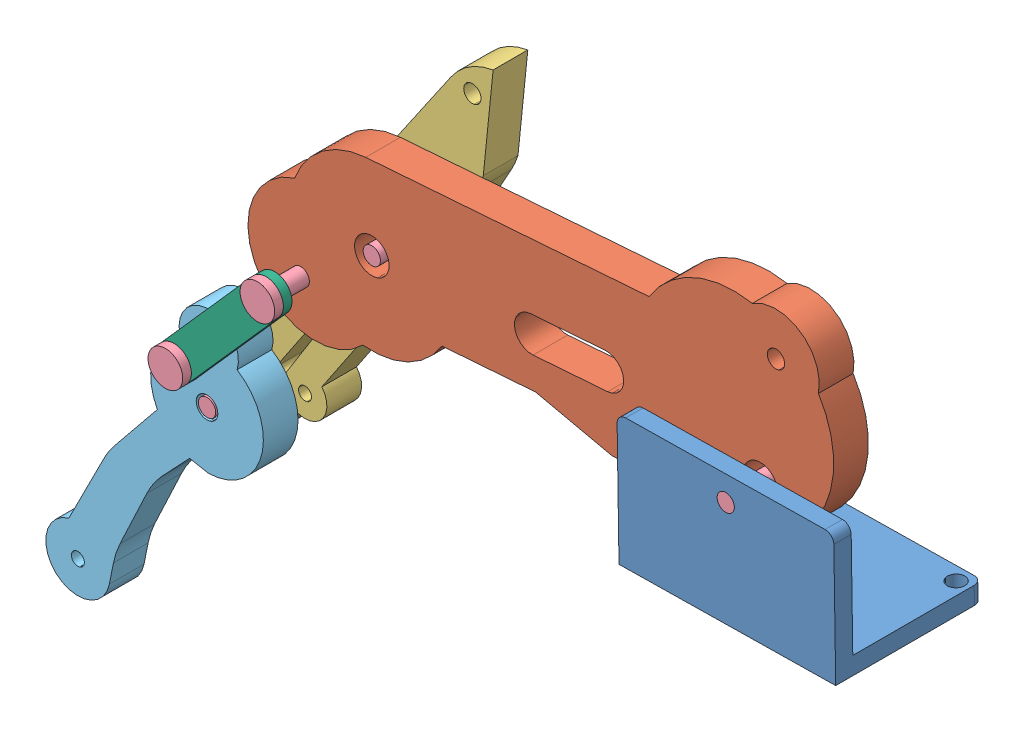
SolidWorks assembly Assem1, configuration Default. Lengths in mm.
Overall size (98.82 77.15 18.06).
10 component instances, 6 part files, 20 mates.
Components (placement in the parent):
- Base-union-1: Base-union [Default] at (40.7368 34.9498 5.6422) x (0.999881 0.015442 0) z (0.015442 -0.999881 0) size (25.11 17.06 15.06)
- Dedo-inferior-1: Dedo-inferior [Default] at (-16.736 45.1395 -0.3578) x (0.997247 0.074154 0) z (0 0 1) size (68.17 25.78 4)
- Dedo-medio-1: Dedo-medio [Default] at (-38.1998 17.0042 -4.3578) x (0.558156 0.829736 0) z (0 0 1) size (59.03 11.38 4)
- Tornillo-0.10-1: Tornillo-0.10 [Default] at (-24.9374 38.9522 -0.3578) x (0.645348 0.763888 0) z (0 0 1) size (4 4 9)
- Tornillo-0.10-2: Tornillo-0.10 [Default] at (-16.736 45.1395 3.6422) x (-0.566388 -0.824139 0) z (0 0 -1) size (4 4 9)
- Tornillo-0.10-3: Tornillo-0.10 [Default] at (28.0815 44.9037 7.6422) x (-0.923728 -0.383049 0) z (0 0 -1) size (4 4 9)
- Tornillo-0.10-4: Tornillo-0.10 [Default] at (-35.5482 26.9767 -0.3578) x (0.999969 -0.007893 0) z (0 0 1) size (4 4 9)
- Tornillo-0.10-5: Tornillo-0.10 [Default] at (-35.7445 20.4797 3.6422) x (0.262 -0.965068 0) z (0 0 -1) size (4 4 9)
- Dedo-punta-1: Dedo-punta [Default] at (-63.5967 -8.6033 -0.3578) x (0.538822 0.84242 0) z (0 0 1) size (39.74 13.26 4)
- Union-2cm-1: Union-2cm [Default] at (-35.5482 26.9767 6.6422) x (0.663175 0.748465 0) z (0 0 1) size (20 4 1)
Mates (geometry in assembly coordinates):
- Concentric6: concentric aligned: circle of Dedo-inferior-1; circle of Tornillo-0.10-1
- Concentric7: concentric aligned: cylinder of Dedo-inferior-1 through (-24.9374 38.9522 3.6422) axis (0 0 -1) radius 1; cylinder of Tornillo-0.10-1 through (-24.9374 38.9522 7.6422) axis (0 0 -1) radius 1
- Coincident10: coincident anti-aligned: plane of Dedo-inferior-1 through (-16.736 45.1395 -0.3578) normal (0 0 -1); circle of Tornillo-0.10-1
- Concentric8: concentric anti-aligned: cylinder of Dedo-inferior-1 through (28.0815 44.9037 3.6422) axis (0 0 -1) radius 2; cylinder of Tornillo-0.10-3 through (28.0815 44.9037 -0.3578) axis (0 0 1) radius 1
- Coincident11: coincident anti-aligned: plane of Dedo-inferior-1 through (-16.736 45.1395 -0.3578) normal (0 0 -1); plane of Tornillo-0.10-3 through (28.0815 44.9037 -0.3578) normal (0 0 1)
- Concentric9: concentric aligned: cylinder of Base-union-1 through (28.0815 44.9037 -24.3578) axis (0 0 1) radius 1; cylinder of Tornillo-0.10-3 through (28.0815 44.9037 -0.3578) axis (0 0 1) radius 1
- Coincident12: coincident aligned: plane of Base-union-1 through (40.7368 34.9498 7.6422) normal (0 0 1); plane of Tornillo-0.10-3 through (28.0815 44.9037 7.6422) normal (0 0 1)
- Coincident14: coincident aligned: plane of Dedo-inferior-1 through (-16.736 45.1395 3.6422) normal (0 0 1); plane of Tornillo-0.10-2 through (-16.736 45.1395 3.6422) normal (0 0 1)
- Concentric11: concentric anti-aligned: cylinder of Dedo-inferior-1 through (-16.736 45.1395 3.6422) axis (0 0 -1) radius 2; cylinder of Tornillo-0.10-2 through (-16.736 45.1395 -4.3578) axis (0 0 1) radius 1
- Concentric22: concentric anti-aligned: cylinder of Tornillo-0.10-5 through (-35.7445 20.4797 -4.3578) axis (0 0 1) radius 1; cylinder of Dedo-punta-1 through (-35.7445 20.4797 3.6422) axis (0 0 -1) radius 1.25
- Coincident25: coincident aligned: plane of Tornillo-0.10-5 through (-35.7445 20.4797 3.6422) normal (0 0 1); plane of Dedo-punta-1 through (-35.7445 20.4797 3.6422) normal (0 0 1)
- Concentric23: concentric aligned: cylinder of Tornillo-0.10-4 through (-35.5482 26.9767 7.6422) axis (0 0 -1) radius 1; cylinder of Dedo-punta-1 through (-35.5482 26.9767 3.6422) axis (0 0 -1) radius 1
- Concentric24: concentric aligned: cylinder of Tornillo-0.10-1 through (-24.9374 38.9522 7.6422) axis (0 0 -1) radius 1; cylinder of Union-2cm-1 through (-24.9374 38.9522 7.6422) axis (0 0 -1) radius 0.8
- Coincident26: coincident anti-aligned: plane of Tornillo-0.10-1 through (-24.9374 38.9522 7.6422) normal (0 0 -1); plane of Union-2cm-1 through (-24.9374 38.9522 7.6422) normal (0 0 1)
- Coincident27: coincident anti-aligned: plane of Tornillo-0.10-4 through (-35.5482 26.9767 7.6422) normal (0 0 -1); plane of Union-2cm-1 through (-24.9374 38.9522 7.6422) normal (0 0 1)
- Concentric25: concentric aligned: cylinder of Tornillo-0.10-4 through (-35.5482 26.9767 7.6422) axis (0 0 -1) radius 1; cylinder of Union-2cm-1 through (-35.5482 26.9767 7.6422) axis (0 0 -1) radius 0.8
- Concentric26: concentric anti-aligned: cylinder of Dedo-medio-1 through (-16.736 45.1395 -0.3578) axis (0 0 -1) radius 1.25; cylinder of Tornillo-0.10-2 through (-16.736 45.1395 -4.3578) axis (0 0 1) radius 1
- Coincident28: coincident anti-aligned: plane of Dedo-medio-1 through (-38.1998 17.0042 -4.3578) normal (0 0 -1); plane of Tornillo-0.10-2 through (-16.736 45.1395 -4.3578) normal (0 0 1)
- Concentric27: concentric anti-aligned: cylinder of Dedo-medio-1 through (-35.7445 20.4797 -0.3578) axis (0 0 -1) radius 1.25; cylinder of Tornillo-0.10-5 through (-35.7445 20.4797 -4.3578) axis (0 0 1) radius 1
- Coincident29: coincident anti-aligned: plane of Dedo-medio-1 through (-38.1998 17.0042 -4.3578) normal (0 0 -1); plane of Tornillo-0.10-5 through (-35.7445 20.4797 -4.3578) normal (0 0 1)
